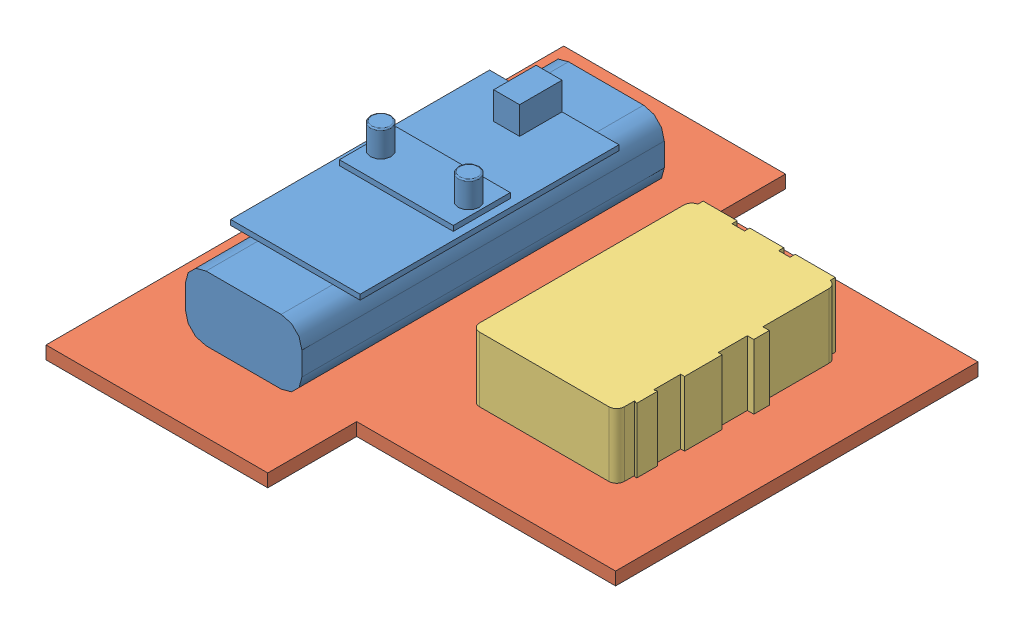
SolidWorks assembly Baugruppe1, configuration Default. Lengths in mm.
Overall size (185.66 44 200).
3 component instances, 3 part files, 2 mates.
Components (placement in the parent):
- AkkuSiluette-1: AkkuSiluette [Default] at (35.2596 63.7873 109.4834) size (50 39 140)
- akkuRaspberryBoden-1: akkuRaspberryBoden [Default] at (175.2161 58.7873 35.755) x (0 0 1) z (-1 0 0) size (200 5 185.66)
- RaspberrySiluette-1: RaspberrySiluette [Standard] at (146.9426 63.7873 147.0794) x (0 0 -1) z (0 1 0) size (87 58.5 25)
Mates (geometry in assembly coordinates):
- Deckungsgleich1: coincident anti-aligned: plane of AkkuSiluette-1 through (35.2596 63.7873 109.4834) normal (0 -1 0); plane of akkuRaspberryBoden-1 through (175.2161 63.7873 35.755) normal (0 1 0)
- Deckungsgleich2: coincident anti-aligned: plane of akkuRaspberryBoden-1 through (175.2161 63.7873 35.755) normal (0 1 0); plane of RaspberrySiluette-1 through (146.9426 63.7873 147.0794) normal (0 -1 0)
